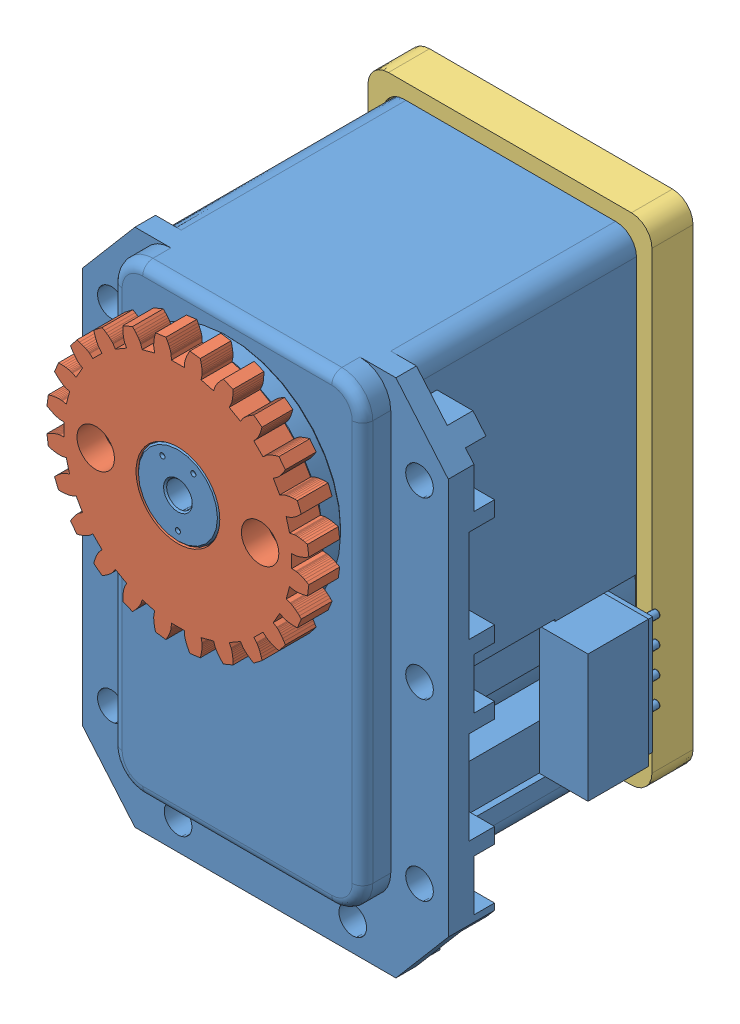
SolidWorks assembly gear_MX-28, configuration Default. Lengths in mm.
Overall size (35.6 52.23 39.77).
3 component instances, 3 part files, 6 mates.
Components (placement in the parent):
- dynamixel MX-28-exposed-1: dynamixel MX-28-exposed [Back Off] at (8.6005 39.3797 35.4547) size (35.6 50.6 39.77)
- w_g1-2: w_g1 [Default] at (8.6005 39.3797 55.9747) size (25.49 25.49 3)
- w_ac-1: w_ac [Default] at (20.9755 51.5047 26.7047) x (0 -1 0) z (0 0 -1) size (48.25 27.65 4)
Mates (geometry in assembly coordinates):
- Coincident1: coincident anti-aligned: plane of dynamixel MX-28-exposed-1 through (8.6005 39.3797 55.9747) normal (0 0 1); plane of w_g1-2 through (8.6005 39.3797 55.9747) normal (0 0 -1)
- Concentric1: concentric anti-aligned: cylinder of dynamixel MX-28-exposed-1 through (8.6005 39.3797 73.2884) axis (0 0 -1) radius 4; cylinder of w_g1-2 through (8.6005 39.3797 55.9747) axis (0 0 1) radius 4.075
- Concentric2: concentric anti-aligned: circle of dynamixel MX-28-exposed-1; circle of w_g1-2
- Concentric3: concentric anti-aligned: circle of dynamixel MX-28-exposed-1; circle of w_ac-1
- Parallel1: parallel aligned: plane of dynamixel MX-28-exposed-1 through (20.8005 51.3797 17.7047) normal (0 1 0); plane of w_ac-1 through (22.4755 53.0047 22.7047) normal (0 1 0)
- Coincident5: coincident anti-aligned: plane of dynamixel MX-28-exposed-1 through (-1.5995 8.3797 26.7047) normal (0 0 -1); plane of w_ac-1 through (20.9755 51.5047 26.7047) normal (0 0 1)
